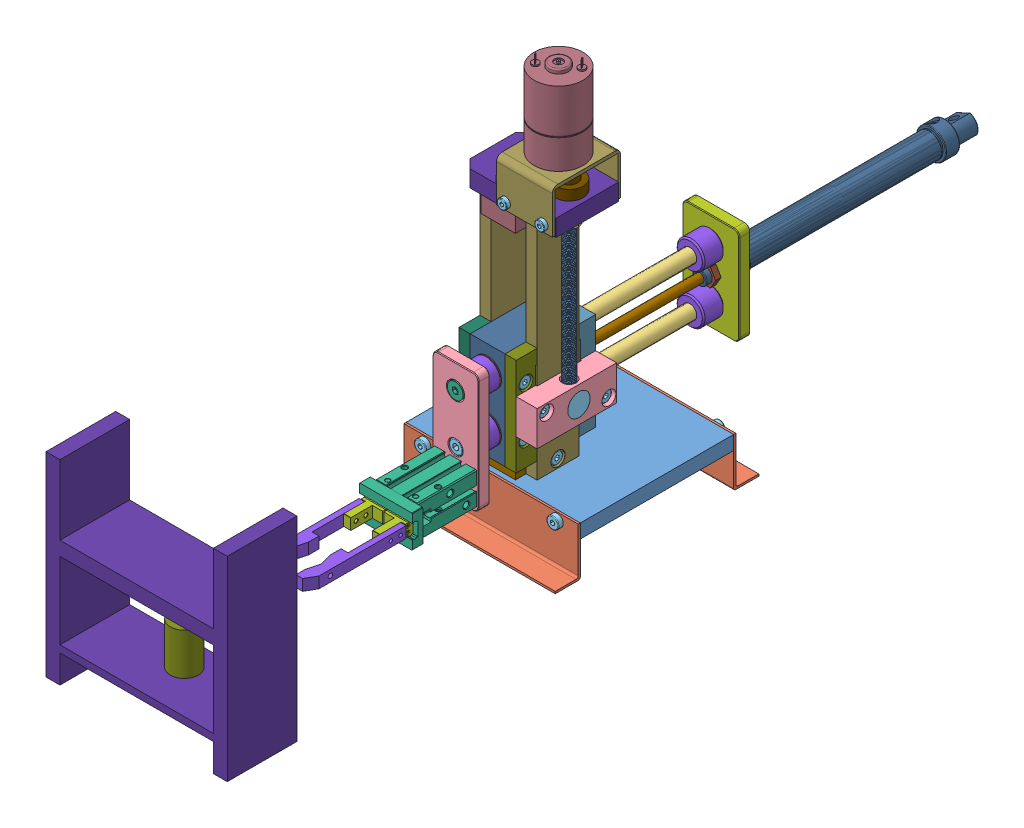
SolidWorks assembly SIm, configuration Default. Lengths in mm.
Overall size (130.9 291 592.3).
74 component instances, 35 part files, 163 mates.
Components (placement in the parent):
- tam_de-1: tam_de [Default] at (55.7373 162.4347 98.3877) size (125 10 110)
- khoi_do-1: khoi_do [Default] at (118.2373 137.4347 153.3877) x (0 0 1) z (0 -1 0) size (18 125 35)
- khoi_do-2: khoi_do [Default] at (-6.7627 137.4347 43.3877) x (0 0 -1) z (0 -1 0) size (18 125 35)
- chot_dan_huong-1: chot_dan_huong [Default] at (55.7373 236.9347 172.3877) x (0.807467 -0.589913 0) z (0.589913 0.807467 0) size (10 175 10)
- chot_dan_huong-2: chot_dan_huong [Default] at (55.7373 201.9347 172.3877) x (0.458763 0.888559 0) z (-0.888559 0.458763 0) size (10 175 10)
- ban_canh_truoc-1: ban_canh_truoc [Default] at (55.7373 211.4347 172.3877) x (1 0 0) z (0 -1 0) size (33 8 86)
- socket head thin cap screw_din-14: socket head thin cap screw_din [DIN 7984 - M5 x 8 --- 5.6N] at (8.2373 167.4347 38.3877) x (0 0 1) z (-1 0 0) size (11.5 8.5 8.5)
- socket head thin cap screw_din-16: socket head thin cap screw_din [DIN 7984 - M5 x 8 --- 5.6N] at (8.2373 167.4347 158.3877) x (0 0 -1) z (1 0 0) size (11.5 8.5 8.5)
- socket head thin cap screw_din-17: socket head thin cap screw_din [DIN 7984 - M5 x 8 --- 5.6N] at (103.2373 167.4347 158.3877) x (0 0 -1) z (1 0 0) size (11.5 8.5 8.5)
- socket head thin cap screw_din-18: socket head thin cap screw_din [DIN 7984 - M5 x 8 --- 5.6N] at (63.2373 164.6347 109.3877) x (0 1 0) z (0 0 1) size (11.5 8.5 8.5)
- socket head thin cap screw_din-19: socket head thin cap screw_din [DIN 7984 - M5 x 8 --- 5.6N] at (48.2373 164.6347 145.3877) x (0 1 0) z (0 0 1) size (11.5 8.5 8.5)
- socket head thin cap screw_din-22: socket head thin cap screw_din [DIN 7984 - M5 x 8 --- 5.6N] at (103.2373 167.4347 38.3877) x (0 0 1) z (-1 0 0) size (11.5 8.5 8.5)
- socket head thin cap screw_din-23: socket head thin cap screw_din [DIN 7984 - M6 x 10 --- 7N] at (55.7373 201.9347 -10.4123) x (0 0 1) z (-1 0 0) size (14 10 10)
- socket head thin cap screw_din-24: socket head thin cap screw_din [DIN 7984 - M6 x 10 --- 7N] at (55.7373 201.6984 180.1877) x (0 0 -1) z (0.997008 0.077294 0) size (14 10 10)
- socket csink head cap screw 10642_din-2: socket csink head cap screw 10642_din [EN ISO 10642 - M6 x 8 - 8N] at (55.7373 236.9347 -10.8323) x (0 0 1) z (-0.997818 -0.066017 0) size (8 11.34 11.34)
- socket csink head cap screw 10642_din-3: socket csink head cap screw 10642_din [EN ISO 10642 - M6 x 8 - 8N] at (55.7373 236.9347 180.6077) x (0 0 -1) z (0.99607 -0.088565 0) size (8 11.34 11.34)
- s3_ban_canh_sau-1: s3_ban_canh_sau [Default] at (55.7373 219.4347 -2.6123) x (-1 0 0) z (0 -1 0) size (41 8 70)
- bac_chan-1: bac_chan [Default] at (55.7373 236.9347 157.3877) x (-0.51421 -0.857665 0) z (-0.857665 0.51421 0) size (20 15 20)
- bac_chan-2: bac_chan [Default] at (55.7373 201.9347 157.3877) x (-0.721448 -0.692468 0) z (-0.692468 0.721448 0) size (20 15 20)
- bac_chan-3: bac_chan [Default] at (55.7373 236.9347 12.3877) x (-0.828899 -0.559398 0) z (0.559398 -0.828899 0) size (20 15 20)
- bac_chan-4: bac_chan [Default] at (55.7373 201.9347 12.3877) x (-0.105421 0.994428 0) z (-0.994428 -0.105421 0) size (20 15 20)
- mieng_dem_duoi-1: mieng_dem_duoi [Default] at (55.7373 172.4347 127.3877) size (25 12 45)
- con_truot_s4_as-1: con_truot_s4_as [Default] at (19.8229 164.1862 110.8419) x (0 0 1) z (0 1 0) size (45 28.02 70)
  - con_truot_s4-1: con_truot_s4 [Default] at (24.0458 23.4144 55.2485) size (45 25 70)
  - bat_lot-1: bat_lot [Default] at (46.5458 35.9144 72.7485) x (0 0.967524 -0.252781) z (0 0.252781 0.967524) size (20 10 20)
  - bat_lot-2: bat_lot [Default] at (46.5458 35.9144 37.7485) x (0 0.967524 -0.252781) z (0 0.252781 0.967524) size (20 10 20)
  - bat_lot-3: bat_lot [Default] at (1.5458 35.9144 72.7485) x (0 0.603074 -0.797685) z (0 -0.797685 -0.603074) size (20 10 20)
  - bat_lot-4: bat_lot [Default] at (1.5458 35.9144 37.7485) x (0 0.603074 -0.797685) z (0 -0.797685 -0.603074) size (20 10 20)
- thanh_dan_huong_lon-1: thanh_dan_huong_lon [Default] at (68.2373 254.9347 127.3877) x (0 0 -1) z (0 -1 0) size (30 8 165)
- thanh_dan_huong_lon-2: thanh_dan_huong_lon [Default] at (43.2373 254.9347 127.3877) x (0 0 -1) z (0 1 0) size (30 8 165)
- mieng_dem_tren-1: mieng_dem_tren [Default] at (55.7373 325.4347 127.3877) size (25 12 45)
- tam_dan_huong-1: tam_dan_huong [Default] at (35.2373 219.4347 106.3877) x (0 0 -1) z (0 -1 0) size (12 41 70)
- thanh_dan_huong_nho_1-1: thanh_dan_huong_nho_1 [Default] at (43.2373 219.4347 149.8877) x (0 0 -1) z (0 1 0) size (15 8 70)
- thanh_dan_huong_nho_2-1: thanh_dan_huong_nho_2 [Default] at (68.2373 219.4347 149.8877) x (0 0 -1) z (0 -1 0) size (15 8 70)
- tam_de_s5-1: tam_de_s5 [Default] at (63.3484 349.4347 127.3877) x (0 0 1) z (1 0 0) size (45 12 67.78)
- dau_kep_truc_vit-1: dau_kep_truc_vit [Default] at (84.2373 339.6347 127.3877) x (0.952744 0 0.303776) z (-0.303776 0 0.952744) size (20 25 20)
- truc_truyen_dong-1: truc_truyen_dong [Default] at (84.2373 208.6347 127.3877) x (0.45612 0 0.889918) z (-0.889918 0 0.45612) size (8.27 150.4 9.24)
- vong_dem-1: vong_dem [Default] at (84.2373 337.4347 127.3877) x (0.916987 0 -0.398918) z (0.398918 0 0.916987) size (19.6 2 19.6)
- hex nut gradec_din-5: hex nut gradec_din [Hexagon Nut ISO 4034 - M8 - N] at (84.2373 329.5347 127.3877) x (-0.92021 0 0.391424) z (0 -1 0) size (13 15.01 7.9)
- thanh_ngang-1: thanh_ngang [Default] at (83.7373 206.9347 128.8877) x (0 0 -1) z (1 0 0) size (57 25 15)
- dai_oc-1: dai_oc [Default] at (77.2373 219.4347 127.3877) x (0 0.924256 0.381773) z (0 0.381773 -0.924256) size (16 14 16)
- socket head thin cap screw_din-25: socket head thin cap screw_din [DIN 7984 - M5 x 8 --- 5.6N] at (89.0373 212.9347 105.8877) x (-1 0 0) z (0 0.924225 0.381849) size (11.5 8.5 8.5)
- socket head thin cap screw_din-26: socket head thin cap screw_din [DIN 7984 - M5 x 8 --- 5.6N] at (89.0373 225.9347 150.3877) x (-1 0 0) z (0 0.924225 0.381849) size (11.5 8.5 8.5)
- socket head thin cap screw_din-27: socket head thin cap screw_din [DIN 7984 - M5 x 8 --- 5.6N] at (75.5373 236.9347 150.3877) x (-1 0 0) z (0 0.924225 0.381849) size (11.5 8.5 8.5)
- socket head thin cap screw_din-28: socket head thin cap screw_din [DIN 7984 - M5 x 8 --- 5.6N] at (75.5373 201.9347 150.3877) x (-1 0 0) z (0 0.924225 0.381849) size (11.5 8.5 8.5)
- socket head thin cap screw_din-29: socket head thin cap screw_din [DIN 7984 - M5 x 8 --- 5.6N] at (75.5373 178.4347 127.3877) x (-1 0 0) z (0 0.924225 0.381849) size (11.5 8.5 8.5)
- socket head thin cap screw_din-30: socket head thin cap screw_din [DIN 7984 - M5 x 8 --- 5.6N] at (35.9373 178.4347 127.3877) size (11.5 8.5 8.5)
- socket head thin cap screw_din-31: socket head thin cap screw_din [DIN 7984 - M5 x 8 --- 5.6N] at (35.9373 201.9347 150.3877) size (11.5 8.5 8.5)
- socket head thin cap screw_din-32: socket head thin cap screw_din [DIN 7984 - M5 x 8 --- 5.6N] at (35.9373 236.9347 150.3877) size (11.5 8.5 8.5)
- socket head thin cap screw_din-33: socket head thin cap screw_din [DIN 7984 - M5 x 8 --- 5.6N] at (35.9373 331.4347 127.3877) size (11.5 8.5 8.5)
- socket head thin cap screw_din-34: socket head thin cap screw_din [DIN 7984 - M5 x 8 --- 5.6N] at (63.2373 248.4347 102.5877) x (0 0 1) z (-1 0 0) size (11.5 8.5 8.5)
- socket head thin cap screw_din-35: socket head thin cap screw_din [DIN 7984 - M5 x 8 --- 5.6N] at (48.2373 190.4347 102.5877) x (0 0 1) z (-1 0 0) size (11.5 8.5 8.5)
- socket head thin cap screw_din-36: socket head thin cap screw_din [DIN 7984 - M5 x 8 --- 5.6N] at (55.7373 352.9347 145.3877) x (0 -1 0) z (0 0 1) size (11.5 8.5 8.5)
- socket head thin cap screw_din-37: socket head thin cap screw_din [DIN 7984 - M5 x 8 --- 5.6N] at (55.7373 352.9347 109.3877) x (0 -1 0) z (0 0 1) size (11.5 8.5 8.5)
- body-2: body [默认] at (55.7373 183.6347 180.3877) x (0 0 -1) z (0 1 0) size (50 38 23.6)
- ljaw-1: ljaw [默认] at (56.1708 183.6347 180.3877) x (0 0 -1) z (0 -1 0) size (21.3 15.4 11.12)
- jaw - ip-2: jaw - ip [Default] at (72.4186 187.6347 268.0848) x (0 0 -1) z (-1 0 0) size (70 8 9.03)
- Part1-1: Part1 [Default] at (55.7373 219.4347 -37.6123) x (0.599964 0.800027 0) z (0.800027 -0.599964 0) size (6.2 165 6.2)
- 16 X 100 Cylinder bore-1: 16 X 100 Cylinder bore [Default] at (55.7373 219.4347 -90.6123) x (-0.421992 0.9066 0) z (0 0 -1) size (21.5 21.5 192)
- hex thin nut gradeb_din-1: hex thin nut gradeb_din [Hexagon Nut ISO 4036 - M8 - N] at (55.7373 219.4347 1.3877) x (0.866025 0.5 0) z (0 0 1) size (13 15.01 4)
- de dong co-1: de dong co [Default] at (96.7373 353.9347 127.4836) x (0 0 1) z (0 -1 0) size (49 40 31)
- moto-1: moto [Default] at (76.7373 371.6519 127.4836) x (0 -1 0) z (-1 0 0) size (63.5 35 35)
- link-1: link [Default] at (91.3829 371.6519 129.7619) x (0 -1 0) z (0.952744 0 0.303776) size (19 10 10)
- socket head thin cap screw_din-39: socket head thin cap screw_din [DIN 7984 - M4 x 6 --- 3.9N] at (63.2373 343.4347 154.7836) x (0 0 -1) z (1 0 0) size (8.8 7 7)
- socket head thin cap screw_din-40: socket head thin cap screw_din [DIN 7984 - M4 x 6 --- 3.9N] at (90.2373 343.4347 100.1836) x (0 0 1) z (-1 0 0) size (8.8 7 7)
- socket head thin cap screw_din-41: socket head thin cap screw_din [DIN 7984 - M4 x 6 --- 3.9N] at (63.2373 343.4347 100.1836) x (0 0 1) z (-1 0 0) size (8.8 7 7)
- socket head thin cap screw_din-44: socket head thin cap screw_din [DIN 7984 - M4 x 6 --- 3.9N] at (90.2373 343.4347 154.7836) x (0 0 -1) z (1 0 0) size (8.8 7 7)
- slotted headless screw_din-5: slotted headless screw_din [DIN 427 M2 x 5 --- 2.4N] at (77.0917 361.1868 125.1094) x (0.952744 0 0.303776) z (-0.303707 -0.021253 0.952528) size (5 2 2)
- socket head thin cap screw_din-45: socket head thin cap screw_din [DIN 7984 - M4 x 10 --- 7.9N] at (66.7373 191.1347 173.9877) x (0 0 1) z (-1 0 0) size (12.8 7 7)
- socket head thin cap screw_din-46: socket head thin cap screw_din [DIN 7984 - M4 x 10 --- 7.9N] at (44.7373 176.1347 173.9877) x (0 0 1) z (-1 0 0) size (12.8 7 7)
- jaw - ip-3: jaw - ip [Default] at (39.056 179.6347 268.0848) x (0 0 -1) z (1 0 0) size (70 8 9.03)
- ljaw-2: ljaw [默认] at (55.3038 183.6347 180.3877) x (0 0 -1) z (0 1 0) size (21.3 15.4 11.12)
- wp-1: wp [Default] at (55.7373 162.4347 374.9086) x (0.821498 0 -0.570212) z (0.570212 0 0.821498) size (20 30 20)
- rack-1: rack [Default] at (52.334 182.4347 355.692) size (130 140 50)
Mates (geometry in assembly coordinates):
- Parallel1: parallel aligned: plane of tam_de-1 through (-6.7627 172.4347 153.3877) normal (0 0 1); plane of khoi_do-1 through (-6.7627 172.4347 154.8877) normal (0 0 1)
- Concentric1: concentric aligned: cylinder of tam_de-1 through (8.2373 167.4347 153.3877) axis (0 0 1) radius 2.1; circle of khoi_do-1
- Concentric2: concentric aligned: circle of tam_de-1; circle of khoi_do-1
- Coincident1: coincident anti-aligned: plane of tam_de-1 through (-6.7627 172.4347 153.3877) normal (0 0 1); plane of khoi_do-1 through (-6.7627 137.4347 153.3877) normal (0 0 -1)
- Parallel2: parallel anti-aligned: plane of tam_de-1 through (-6.7627 172.4347 43.3877) normal (0 0 -1); plane of khoi_do-2 through (118.2373 137.4347 43.3877) normal (0 0 1)
- Concentric3: concentric aligned: circle of tam_de-1; cylinder of khoi_do-2 through (8.2373 167.4347 43.3877) axis (0 0 -1) radius 2.75
- Parallel3: parallel aligned: plane of tam_de-1 through (55.7373 172.4347 98.3877) normal (0 1 0); plane of khoi_do-2 through (118.2373 172.4347 43.3877) normal (0 1 0)
- Coincident2: coincident anti-aligned: plane of tam_de-1 through (-6.7627 172.4347 43.3877) normal (0 0 -1); plane of khoi_do-2 through (118.2373 137.4347 43.3877) normal (0 0 1)
- Concentric18: concentric aligned: cylinder of chot_dan_huong-2 through (55.7373 201.9347 172.3877) axis (0 0 1) radius 2.5; circle of ban_canh_truoc-1
- Concentric19: concentric anti-aligned: circle of chot_dan_huong-1; circle of ban_canh_truoc-1
- Coincident14: coincident aligned: plane of chot_dan_huong-1 through (55.7373 236.9347 172.3877) normal (0 0 1); circle of ban_canh_truoc-1
- Coincident15: coincident aligned: circle of chot_dan_huong-2; plane of ban_canh_truoc-1 through (55.7373 211.4347 172.3877) normal (0 0 -1)
- Concentric37: concentric aligned: cylinder of khoi_do-2 through (8.2373 167.4347 43.3877) axis (0 0 -1) radius 2.75; cylinder of socket head thin cap screw_din-14 through (8.2373 167.4347 6.6377) axis (0 0 -1) radius 4.25
- Coincident28: coincident anti-aligned: plane of khoi_do-2 through (118.2373 172.4347 41.8877) normal (0 0 -1); plane of socket head thin cap screw_din-14 through (8.2373 171.6847 41.8877) normal (0 0 1)
- Concentric39: concentric aligned: cylinder of khoi_do-1 through (8.2373 167.4347 153.3877) axis (0 0 1) radius 2.75; cylinder of socket head thin cap screw_din-16 through (8.2373 167.4347 190.1377) axis (0 0 1) radius 4.25
- Coincident30: coincident anti-aligned: plane of khoi_do-1 through (-6.7627 172.4347 154.8877) normal (0 0 1); plane of socket head thin cap screw_din-16 through (8.2373 171.6847 154.8877) normal (0 0 -1)
- Concentric40: concentric aligned: cylinder of khoi_do-1 through (103.2373 167.4347 153.3877) axis (0 0 1) radius 2.75; cylinder of socket head thin cap screw_din-17 through (103.2373 167.4347 190.1377) axis (0 0 1) radius 4.25
- Coincident31: coincident anti-aligned: plane of khoi_do-1 through (-6.7627 172.4347 154.8877) normal (0 0 1); plane of socket head thin cap screw_din-17 through (103.2373 171.6847 154.8877) normal (0 0 -1)
- Concentric41: concentric aligned: cylinder of tam_de-1 through (63.2373 172.4347 109.3877) axis (0 -1 0) radius 2.75; cylinder of socket head thin cap screw_din-18 through (63.2373 132.8847 109.3877) axis (0 -1 0) radius 4.25
- Coincident32: coincident anti-aligned: plane of tam_de-1 through (63.2373 168.1347 109.3877) normal (0 -1 0); plane of socket head thin cap screw_din-18 through (58.9873 168.1347 109.3877) normal (0 1 0)
- Concentric42: concentric aligned: cylinder of tam_de-1 through (48.2373 172.4347 145.3877) axis (0 -1 0) radius 2.75; cylinder of socket head thin cap screw_din-19 through (48.2373 132.8847 145.3877) axis (0 -1 0) radius 4.25
- Coincident33: coincident anti-aligned: plane of tam_de-1 through (48.2373 168.1347 145.3877) normal (0 -1 0); plane of socket head thin cap screw_din-19 through (43.9873 168.1347 145.3877) normal (0 1 0)
- Concentric451: concentric aligned: cylinder of khoi_do-2 through (103.2373 167.4347 43.3877) axis (0 0 -1) radius 2.75; cylinder of socket head thin cap screw_din-22 through (103.2373 167.4347 6.6377) axis (0 0 -1) radius 4.25
- Coincident361: coincident anti-aligned: plane of khoi_do-2 through (118.2373 172.4347 41.8877) normal (0 0 -1); plane of socket head thin cap screw_din-22 through (103.2373 171.6847 41.8877) normal (0 0 1)
- Concentric47: concentric aligned: cylinder of ban_canh_truoc-1 through (55.7373 201.6984 176.1877) axis (0 0 1) radius 5.5; cylinder of socket head thin cap screw_din-24 through (55.7373 201.6984 211.9377) axis (0 0 1) radius 5
- Coincident38: coincident anti-aligned: plane of ban_canh_truoc-1 through (55.7373 201.6984 176.1877) normal (0 0 1); plane of socket head thin cap screw_din-24 through (55.3508 206.6834 176.1877) normal (0 0 -1)
- Coincident40: coincident aligned: cone of ban_canh_truoc-1 through (55.7373 236.9347 177.1877) axis (0 0 -1); cylinder of socket csink head cap screw 10642_din-3 through (55.7373 236.9347 179.5577) axis (0 0 -1) radius 785.3982
- Concentric452: concentric aligned: circle of chot_dan_huong-2; circle of s3_ban_canh_sau-1
- Coincident362: coincident anti-aligned: plane of chot_dan_huong-1 through (55.7373 236.9347 -2.6123) normal (0 0 -1); plane of s3_ban_canh_sau-1 through (55.7373 219.4347 -2.6123) normal (0 0 1)
- Concentric453: concentric anti-aligned: cylinder of socket csink head cap screw 10642_din-2 through (55.7373 236.9347 -10.8323) axis (0 0 -1) radius 3; cylinder of s3_ban_canh_sau-1 through (55.7373 236.9347 -10.6123) axis (0 0 1) radius 3.3
- Coincident363: coincident aligned: cylinder of socket csink head cap screw 10642_din-2 through (55.7373 236.9347 -9.7823) axis (0 0 1) radius 785.3982; cylinder of s3_ban_canh_sau-1 through (55.7373 236.9347 -7.4123) axis (0 0 1) radius 785.3982
- Concentric454: concentric aligned: cylinder of chot_dan_huong-2 through (55.7373 201.9347 -2.6123) axis (0 0 -1) radius 2.5; cylinder of socket head thin cap screw_din-23 through (55.7373 201.9347 -42.1623) axis (0 0 -1) radius 3
- Coincident364: coincident anti-aligned: plane of socket head thin cap screw_din-23 through (55.7373 206.9347 -6.4123) normal (0 0 1); plane of s3_ban_canh_sau-1 through (55.7373 201.9347 -6.4123) normal (0 0 -1)
- Concentric456: concentric anti-aligned: cylinder of chot_dan_huong-1 through (55.7373 236.9347 -2.6123) axis (0 0 1) radius 5; cylinder of bac_chan-1 through (55.7373 236.9347 172.3877) axis (0 0 -1) radius 5
- Coincident366: coincident anti-aligned: plane of ban_canh_truoc-1 through (55.7373 211.4347 172.3877) normal (0 0 -1); plane of bac_chan-1 through (55.7373 236.9347 172.3877) normal (0 0 1)
- Concentric457: concentric anti-aligned: cylinder of chot_dan_huong-2 through (55.7373 201.9347 -2.6123) axis (0 0 1) radius 5; circle of bac_chan-2
- Coincident367: coincident anti-aligned: plane of ban_canh_truoc-1 through (55.7373 211.4347 172.3877) normal (0 0 -1); plane of bac_chan-2 through (55.7373 201.9347 172.3877) normal (0 0 1)
- Concentric458: concentric anti-aligned: cylinder of chot_dan_huong-1 through (55.7373 236.9347 -2.6123) axis (0 0 1) radius 5; circle of bac_chan-3
- Coincident368: coincident anti-aligned: plane of s3_ban_canh_sau-1 through (55.7373 219.4347 -2.6123) normal (0 0 1); plane of bac_chan-3 through (55.7373 236.9347 -2.6123) normal (0 0 -1)
- Concentric459: concentric anti-aligned: cylinder of chot_dan_huong-2 through (55.7373 201.9347 -2.6123) axis (0 0 1) radius 5; circle of bac_chan-4
- Coincident369: coincident anti-aligned: plane of s3_ban_canh_sau-1 through (55.7373 219.4347 -2.6123) normal (0 0 1); plane of bac_chan-4 through (55.7373 201.9347 -2.6123) normal (0 0 -1)
- Concentric460: concentric anti-aligned: cylinder of socket head thin cap screw_din-19 through (48.2373 132.8847 145.3877) axis (0 -1 0) radius 2.5; cylinder of mieng_dem_duoi-1 through (48.2373 184.4347 145.3877) axis (0 1 0) radius 2.1
- Concentric461: concentric anti-aligned: cylinder of socket head thin cap screw_din-18 through (63.2373 132.8847 109.3877) axis (0 -1 0) radius 2.5; cylinder of mieng_dem_duoi-1 through (63.2373 184.4347 109.3877) axis (0 1 0) radius 2.1
- Coincident371: coincident anti-aligned: plane of tam_de-1 through (55.7373 172.4347 98.3877) normal (0 1 0); plane of mieng_dem_duoi-1 through (55.7373 172.4347 127.3877) normal (0 -1 0)
- Parallel6: parallel anti-aligned: plane of mieng_dem_duoi-1 through (55.7373 184.4347 127.3877) normal (0 1 0); plane of con_truot_s4_as-1/con_truot_s4-1 through (226.6799 184.4347 112.3877) normal (0 -1 0)
- Parallel7: parallel aligned: plane of mieng_dem_duoi-1 through (68.2373 184.4347 149.8877) normal (1 0 0); plane of con_truot_s4_as-1/con_truot_s4-1 through (68.2373 219.4347 134.8877) normal (1 0 0)
- Coincident372: coincident aligned: plane of mieng_dem_duoi-1 through (68.2373 184.4347 149.8877) normal (1 0 0); plane of con_truot_s4_as-1/con_truot_s4-1 through (68.2373 219.4347 134.8877) normal (1 0 0)
- Concentric464: concentric aligned: cylinder of chot_dan_huong-2 through (55.7373 201.9347 -2.6123) axis (0 0 1) radius 5; cylinder of con_truot_s4_as-1/bat_lot-2 through (55.7373 201.9347 147.3877) axis (0 0 1) radius 5
- Concentric465: concentric aligned: cylinder of chot_dan_huong-1 through (55.7373 236.9347 -2.6123) axis (0 0 1) radius 5; circle of con_truot_s4_as-1/con_truot_s4-1
- Parallel9: parallel aligned: plane of con_truot_s4_as-1/con_truot_s4-1 through (68.2373 219.4347 134.8877) normal (1 0 0); plane of thanh_dan_huong_lon-1 through (76.2373 254.9347 127.3877) normal (1 0 0)
- Concentric466: concentric anti-aligned: circle of mieng_dem_duoi-1; circle of thanh_dan_huong_lon-1
- Parallel10: parallel aligned: plane of con_truot_s4_as-1/con_truot_s4-1 through (68.2373 270.4347 112.3877) normal (0 0 -1); plane of thanh_dan_huong_lon-1 through (76.2373 172.4347 112.3877) normal (0 0 -1)
- Coincident374: coincident anti-aligned: plane of mieng_dem_duoi-1 through (68.2373 184.4347 149.8877) normal (1 0 0); plane of thanh_dan_huong_lon-1 through (68.2373 254.9347 127.3877) normal (-1 0 0)
- Parallel11: parallel: line of thanh_dan_huong_lon-1 through (68.2373 337.3347 112.4877) axis (0 -1 0); plane of thanh_dan_huong_lon-2 through (35.2373 337.4347 142.3877) normal (0 0 1)
- Parallel12: parallel aligned: plane of thanh_dan_huong_lon-1 through (68.2373 254.9347 127.3877) normal (-1 0 0); plane of thanh_dan_huong_lon-2 through (35.2373 254.9347 127.3877) normal (-1 0 0)
- Concentric467: concentric anti-aligned: cylinder of mieng_dem_duoi-1 through (68.2373 178.4347 127.3877) axis (1 0 0) radius 2.1; circle of thanh_dan_huong_lon-2
- Coincident375: coincident anti-aligned: plane of mieng_dem_duoi-1 through (43.2373 184.4347 149.8877) normal (-1 0 0); plane of thanh_dan_huong_lon-2 through (43.2373 254.9347 127.3877) normal (1 0 0)
- Concentric468: concentric aligned: cylinder of thanh_dan_huong_lon-2 through (39.4373 331.4347 127.3877) axis (-1 0 0) radius 5; cylinder of mieng_dem_tren-1 through (43.2373 331.4347 127.3877) axis (-1 0 0) radius 2.1
- Parallel13: parallel aligned: plane of mieng_dem_duoi-1 through (55.7373 184.4347 127.3877) normal (0 1 0); plane of mieng_dem_tren-1 through (55.7373 337.4347 127.3877) normal (0 1 0)
- Coincident376: coincident anti-aligned: plane of thanh_dan_huong_lon-2 through (43.2373 254.9347 127.3877) normal (1 0 0); plane of mieng_dem_tren-1 through (43.2373 337.4347 149.8877) normal (-1 0 0)
- Parallel14: parallel anti-aligned: plane of con_truot_s4_as-1/con_truot_s4-1 through (68.2373 270.4347 112.3877) normal (0 0 -1); plane of tam_dan_huong-1 through (76.2373 244.4347 111.3877) normal (0 0 1)
- Parallel15: parallel anti-aligned: plane of con_truot_s4_as-1/con_truot_s4-1 through (193.5245 254.4347 112.3877) normal (0 1 0); plane of tam_dan_huong-1 through (76.2373 184.4347 112.3877) normal (0 -1 0)
- Concentric469: concentric aligned: circle of con_truot_s4_as-1/con_truot_s4-1; circle of tam_dan_huong-1
- Coincident377: coincident anti-aligned: plane of con_truot_s4_as-1/con_truot_s4-1 through (68.2373 270.4347 112.3877) normal (0 0 -1); plane of tam_dan_huong-1 through (76.2373 244.4347 112.3877) normal (0 0 1)
- Concentric470: concentric anti-aligned: circle of con_truot_s4_as-1/con_truot_s4-1; circle of thanh_dan_huong_nho_1-1
- Concentric474: concentric anti-aligned: cylinder of con_truot_s4_as-1/con_truot_s4-1 through (68.2373 201.9347 150.3877) axis (1 0 0) radius 2.1; cylinder of thanh_dan_huong_nho_1-1 through (39.4373 201.9347 150.3877) axis (-1 0 0) radius 5
- Coincident378: coincident anti-aligned: plane of con_truot_s4_as-1/con_truot_s4-1 through (43.2373 219.4347 134.8877) normal (-1 0 0); plane of thanh_dan_huong_nho_1-1 through (43.2373 219.4347 149.8877) normal (1 0 0)
- Coincident379: coincident anti-aligned: plane of thanh_dan_huong_lon-2 through (35.2373 337.4347 112.3877) normal (0 0 -1); plane of tam_dan_huong-1 through (76.2373 244.4347 112.3877) normal (0 0 1)
- Concentric475: concentric anti-aligned: circle of con_truot_s4_as-1/con_truot_s4-1; circle of thanh_dan_huong_nho_2-1
- Concentric476: concentric anti-aligned: circle of con_truot_s4_as-1/con_truot_s4-1; circle of thanh_dan_huong_nho_2-1
- Coincident380: coincident anti-aligned: plane of con_truot_s4_as-1/con_truot_s4-1 through (68.2373 219.4347 134.8877) normal (1 0 0); plane of thanh_dan_huong_nho_2-1 through (68.2373 219.4347 149.8877) normal (-1 0 0)
- Coincident381: coincident anti-aligned: plane of s3_ban_canh_sau-1 through (55.7373 219.4347 -2.6123) normal (0 0 1); plane of bac_chan-3 through (55.7373 236.9347 -2.6123) normal (0 0 -1)
- Concentric477: concentric aligned: circle of s3_ban_canh_sau-1; circle of bac_chan-3
- Axis Y: limit distance = 0 mm anti-aligned: plane of con_truot_s4_as-1/con_truot_s4-1 through (226.6799 184.4347 112.3877) normal (0 -1 0); plane of mieng_dem_duoi-1 through (55.7373 184.4347 127.3877) normal (0 1 0)
- Parallel16: parallel anti-aligned: plane of mieng_dem_tren-1 through (55.7373 337.4347 127.3877) normal (0 1 0); plane of tam_de_s5-1 through (63.3484 337.4347 127.3877) normal (0 -1 0)
- Parallel17: parallel anti-aligned: plane of thanh_dan_huong_lon-1 through (76.2373 254.9347 127.3877) normal (1 0 0); plane of tam_de_s5-1 through (29.4595 337.4347 110.8877) normal (-1 0 0)
- Concentric478: concentric anti-aligned: cylinder of tam_de_s5-1 through (84.2373 337.4347 127.3877) axis (0 1 0) radius 7; cylinder of dau_kep_truc_vit-1 through (84.2373 349.4347 127.3877) axis (0 -1 0) radius 7
- Coincident382: coincident anti-aligned: plane of tam_de_s5-1 through (63.3484 349.4347 127.3877) normal (0 1 0); plane of dau_kep_truc_vit-1 through (84.2373 349.4347 127.3877) normal (0 -1 0)
- Concentric479: concentric aligned: cylinder of mieng_dem_tren-1 through (55.7373 337.4347 145.3877) axis (0 1 0) radius 2.1; cylinder of tam_de_s5-1 through (55.7373 337.4347 145.3877) axis (0 1 0) radius 2.75
- Coincident383: coincident anti-aligned: plane of mieng_dem_tren-1 through (55.7373 337.4347 127.3877) normal (0 1 0); plane of tam_de_s5-1 through (63.3484 337.4347 127.3877) normal (0 -1 0)
- Concentric480: concentric anti-aligned: cylinder of dau_kep_truc_vit-1 through (84.2373 339.6347 127.3877) axis (0 -1 0) radius 3.4; circle of truc_truyen_dong-1
- Coincident384: coincident anti-aligned: plane of dau_kep_truc_vit-1 through (84.2373 356.6347 127.3877) normal (0 -1 0); plane of truc_truyen_dong-1 through (84.2373 356.6347 127.3877) normal (0 1 0)
- Concentric481: concentric aligned: cylinder of tam_de_s5-1 through (84.2373 339.9347 127.3877) axis (0 -1 0) radius 10; cylinder of vong_dem-1 through (84.2373 339.4347 127.3877) axis (0 -1 0) radius 9.8
- Coincident385: coincident aligned: plane of tam_de_s5-1 through (63.3484 337.4347 127.3877) normal (0 -1 0); plane of vong_dem-1 through (84.2373 337.4347 127.3877) normal (0 -1 0)
- Concentric484: concentric aligned: cylinder of vong_dem-1 through (84.2373 339.4347 127.3877) axis (0 -1 0) radius 4.25; cylinder of hex nut gradec_din-5 through (84.2373 354.5722 127.3877) axis (0 -1 0) radius 4
- Coincident387: coincident anti-aligned: plane of vong_dem-1 through (84.2373 337.4347 127.3877) normal (0 -1 0); plane of hex nut gradec_din-5 through (81.2995 337.4347 120.481) normal (0 1 0)
- Lock1: lock: unknown of dau_kep_truc_vit-1; unknown of vong_dem-1
- Lock2: lock: unknown of vong_dem-1; unknown of hex nut gradec_din-5
- Lock3: lock: unknown of truc_truyen_dong-1; unknown of hex nut gradec_din-5
- Parallel18: parallel aligned: plane of thanh_dan_huong_lon-1 through (76.2373 254.9347 127.3877) normal (1 0 0); plane of thanh_ngang-1 through (91.2373 231.9347 157.3877) normal (1 0 0)
- Parallel19: parallel aligned: plane of thanh_dan_huong_nho_2-1 through (76.2373 184.4347 157.3877) normal (0 0 1); plane of thanh_ngang-1 through (91.2373 231.9347 157.3877) normal (0 0 1)
- Concentric485: concentric aligned: cylinder of thanh_dan_huong_nho_2-1 through (76.2373 225.9347 150.3877) axis (1 0 0) radius 2.1; cylinder of thanh_ngang-1 through (76.2373 225.9347 150.3877) axis (1 0 0) radius 2.75
- Coincident388: coincident anti-aligned: plane of thanh_dan_huong_nho_2-1 through (76.2373 219.4347 149.8877) normal (1 0 0); plane of thanh_ngang-1 through (76.2373 231.9347 157.3877) normal (-1 0 0)
- Concentric486: concentric anti-aligned: circle of truc_truyen_dong-1; cylinder of dai_oc-1 through (84.2373 227.4347 127.3877) axis (0 1 0) radius 3.4
- Concentric487: concentric aligned: circle of thanh_ngang-1; circle of dai_oc-1
- Concentric488: concentric aligned: cylinder of thanh_ngang-1 through (76.2373 212.9347 105.8877) axis (1 0 0) radius 2.75; cylinder of socket head thin cap screw_din-25 through (120.7873 212.9347 105.8877) axis (1 0 0) radius 4.25
- Coincident389: coincident anti-aligned: plane of thanh_ngang-1 through (85.5373 212.9347 105.8877) normal (1 0 0); plane of socket head thin cap screw_din-25 through (85.5373 211.3118 109.8157) normal (-1 0 0)
- Concentric489: concentric aligned: cylinder of thanh_ngang-1 through (76.2373 225.9347 150.3877) axis (1 0 0) radius 2.75; cylinder of socket head thin cap screw_din-26 through (120.7873 225.9347 150.3877) axis (1 0 0) radius 4.25
- Coincident390: coincident anti-aligned: plane of thanh_ngang-1 through (85.5373 225.9347 150.3877) normal (1 0 0); plane of socket head thin cap screw_din-26 through (85.5373 224.3118 154.3157) normal (-1 0 0)
- Concentric490: concentric aligned: cylinder of thanh_dan_huong_nho_2-1 through (72.0373 236.9347 150.3877) axis (1 0 0) radius 5; cylinder of socket head thin cap screw_din-27 through (107.2873 236.9347 150.3877) axis (1 0 0) radius 4.25
- Coincident391: coincident anti-aligned: plane of thanh_dan_huong_nho_2-1 through (72.0373 236.9347 150.3877) normal (1 0 0); plane of socket head thin cap screw_din-27 through (72.0373 235.3118 154.3157) normal (-1 0 0)
- Concentric491: concentric aligned: cylinder of thanh_dan_huong_nho_2-1 through (72.0373 201.9347 150.3877) axis (1 0 0) radius 5; cylinder of socket head thin cap screw_din-28 through (107.2873 201.9347 150.3877) axis (1 0 0) radius 4.25
- Coincident392: coincident anti-aligned: plane of thanh_dan_huong_nho_2-1 through (72.0373 201.9347 150.3877) normal (1 0 0); plane of socket head thin cap screw_din-28 through (72.0373 200.3118 154.3157) normal (-1 0 0)
- Concentric492: concentric aligned: cylinder of thanh_dan_huong_lon-1 through (72.0373 178.4347 127.3877) axis (1 0 0) radius 5; cylinder of socket head thin cap screw_din-29 through (107.2873 178.4347 127.3877) axis (1 0 0) radius 4.25
- Coincident393: coincident anti-aligned: plane of thanh_dan_huong_lon-1 through (72.0373 178.4347 127.3877) normal (1 0 0); plane of socket head thin cap screw_din-29 through (72.0373 176.8118 131.3157) normal (-1 0 0)
- Concentric493: concentric anti-aligned: cylinder of thanh_dan_huong_lon-2 through (35.2373 178.4347 127.3877) axis (1 0 0) radius 2.75; cylinder of socket head thin cap screw_din-30 through (4.1873 178.4347 127.3877) axis (-1 0 0) radius 4.25
- Coincident394: coincident anti-aligned: plane of thanh_dan_huong_lon-2 through (39.4373 178.4347 127.3877) normal (-1 0 0); plane of socket head thin cap screw_din-30 through (39.4373 182.6847 127.3877) normal (1 0 0)
- Concentric494: concentric aligned: cylinder of thanh_dan_huong_nho_1-1 through (39.4373 201.9347 150.3877) axis (-1 0 0) radius 5; cylinder of socket head thin cap screw_din-31 through (4.1873 201.9347 150.3877) axis (-1 0 0) radius 4.25
- Coincident395: coincident anti-aligned: plane of thanh_dan_huong_nho_1-1 through (39.4373 201.9347 150.3877) normal (-1 0 0); plane of socket head thin cap screw_din-31 through (39.4373 206.1847 150.3877) normal (1 0 0)
- Concentric495: concentric aligned: cylinder of thanh_dan_huong_nho_1-1 through (39.4373 236.9347 150.3877) axis (-1 0 0) radius 5; cylinder of socket head thin cap screw_din-32 through (4.1873 236.9347 150.3877) axis (-1 0 0) radius 4.25
- Coincident396: coincident anti-aligned: plane of thanh_dan_huong_nho_1-1 through (39.4373 236.9347 150.3877) normal (-1 0 0); plane of socket head thin cap screw_din-32 through (39.4373 241.1847 150.3877) normal (1 0 0)
- Concentric496: concentric aligned: cylinder of thanh_dan_huong_lon-2 through (39.4373 331.4347 127.3877) axis (-1 0 0) radius 5; cylinder of socket head thin cap screw_din-33 through (4.1873 331.4347 127.3877) axis (-1 0 0) radius 4.25
- Coincident397: coincident anti-aligned: plane of thanh_dan_huong_lon-2 through (39.4373 331.4347 127.3877) normal (-1 0 0); plane of socket head thin cap screw_din-33 through (39.4373 335.6847 127.3877) normal (1 0 0)
- Concentric497: concentric aligned: cylinder of tam_dan_huong-1 through (63.2373 248.4347 112.3877) axis (0 0 -1) radius 2.75; cylinder of socket head thin cap screw_din-34 through (63.2373 248.4347 70.8377) axis (0 0 -1) radius 4.25
- Coincident398: coincident anti-aligned: plane of tam_dan_huong-1 through (63.2373 248.4347 106.0877) normal (0 0 -1); plane of socket head thin cap screw_din-34 through (63.2373 252.6847 106.0877) normal (0 0 1)
- Concentric498: concentric aligned: cylinder of tam_dan_huong-1 through (48.2373 190.4347 112.3877) axis (0 0 -1) radius 2.75; cylinder of socket head thin cap screw_din-35 through (48.2373 190.4347 70.8377) axis (0 0 -1) radius 4.25
- Coincident399: coincident anti-aligned: plane of tam_dan_huong-1 through (48.2373 190.4347 106.0877) normal (0 0 -1); plane of socket head thin cap screw_din-35 through (48.2373 194.6847 106.0877) normal (0 0 1)
- Concentric499: concentric aligned: cylinder of tam_de_s5-1 through (55.7373 337.4347 145.3877) axis (0 1 0) radius 2.75; cylinder of socket head thin cap screw_din-36 through (55.7373 384.6847 145.3877) axis (0 1 0) radius 4.25
- Coincident401: coincident anti-aligned: plane of tam_de_s5-1 through (63.3484 349.4347 127.3877) normal (0 1 0); plane of socket head thin cap screw_din-36 through (59.9873 349.4347 145.3877) normal (0 -1 0)
- Concentric500: concentric aligned: cylinder of tam_de_s5-1 through (55.7373 337.4347 109.3877) axis (0 1 0) radius 2.75; cylinder of socket head thin cap screw_din-37 through (55.7373 384.6847 109.3877) axis (0 1 0) radius 4.25
- Coincident402: coincident anti-aligned: plane of tam_de_s5-1 through (63.3484 349.4347 127.3877) normal (0 1 0); plane of socket head thin cap screw_din-37 through (59.9873 349.4347 109.3877) normal (0 -1 0)
- Concentric507: concentric aligned: cylinder of ban_canh_truoc-1 through (44.7373 176.1347 180.3877) axis (0 0 -1) radius 2.25; cylinder of body-2 through (44.7373 176.1347 184.8272) axis (0 0 -1) radius 1.621
- Coincident405: coincident anti-aligned: plane of ban_canh_truoc-1 through (55.7373 211.4347 180.3877) normal (0 0 1); plane of body-2 through (55.7373 183.6347 180.3877) normal (0 0 -1)
- Concentric509: concentric aligned: cylinder of ban_canh_truoc-1 through (66.7373 191.1347 180.3877) axis (0 0 -1) radius 2.25; cylinder of body-2 through (66.7373 191.1347 184.8272) axis (0 0 -1) radius 1.621
- Concentric510: concentric anti-aligned: cylinder of body-2 through (36.7373 188.7947 228.6877) axis (-1 0 0) radius 0.4; cylinder of ljaw-1 through (11.1708 188.7947 228.6877) axis (1 0 0) radius 0.4
- Parallel20: parallel aligned: plane of body-2 through (55.7373 183.6347 230.3877) normal (0 0 1); plane of ljaw-1 through (56.1808 179.6347 232.1877) normal (0 0 1)
- Gripper: limit distance = 0.4435 mm: point of ljaw-1; moEndPointRef_w of body-2
- Concentric514: concentric aligned: cylinder of ljaw-1 through (66.1258 183.6347 236.6877) axis (1 0 0) radius 1.2295; cylinder of jaw - ip-2 through (72.6308 183.6347 236.6877) axis (1 0 0) radius 1.25
- Concentric515: concentric aligned: cylinder of ljaw-1 through (66.1258 183.6347 243.6877) axis (1 0 0) radius 1.2295; cylinder of jaw - ip-2 through (72.6308 183.6347 243.6877) axis (1 0 0) radius 1.25
- Coincident407: coincident anti-aligned: plane of ljaw-1 through (68.6308 183.6347 180.3877) normal (1 0 0); plane of jaw - ip-2 through (68.6308 179.6347 270.368) normal (-1 0 0)
- Axis Z: limit distance = 0 mm anti-aligned: plane of bac_chan-1 through (55.7373 236.9347 157.3877) normal (0 0 -1); plane of con_truot_s4_as-1/con_truot_s4-1 through (68.2373 270.4347 157.3877) normal (0 0 1)
- Concentric518: concentric aligned: cylinder of con_truot_s4_as-1/con_truot_s4-1 through (55.7373 219.4347 112.3877) axis (0 0 -1) radius 2.1; cylinder of Part1-1 through (55.7373 219.4347 108.3877) axis (0 0 -1) radius 2.6
- Coincident408: coincident anti-aligned: circle of con_truot_s4_as-1/con_truot_s4-1; plane of Part1-1 through (55.7373 219.4347 127.3877) normal (0 0 1)
- Concentric519: concentric anti-aligned: cylinder of Part1-1 through (55.7373 219.4347 127.3877) axis (0 0 -1) radius 3.1; cylinder of 16 X 100 Cylinder bore-1 through (55.7373 219.4347 -169.6123) axis (0 0 1) radius 3.25
- Coincident409: coincident anti-aligned: plane of s3_ban_canh_sau-1 through (55.7373 219.4347 -6.4123) normal (0 0 -1); plane of 16 X 100 Cylinder bore-1 through (55.7373 219.4347 -6.4123) normal (0 0 1)
- Concentric521: concentric aligned: cylinder of 16 X 100 Cylinder bore-1 through (55.7373 219.4347 -37.0085) axis (0 0 1) radius 5.1; cylinder of hex thin nut gradeb_din-1 through (55.7373 219.4347 -23.6498) axis (0 0 1) radius 4
- Coincident410: coincident anti-aligned: plane of s3_ban_canh_sau-1 through (55.7373 219.4347 -2.6123) normal (0 0 1); plane of hex thin nut gradeb_din-1 through (51.9845 225.9347 -2.6123) normal (0 0 -1)
- Parallel24: parallel aligned: plane of s3_ban_canh_sau-1 through (76.2373 254.4347 -10.6123) normal (0 1 0); plane of hex thin nut gradeb_din-1 through (59.4901 225.9347 -2.6123) normal (0 1 0)
- Concentric522: concentric anti-aligned: cylinder of tam_de_s5-1 through (90.2373 343.4347 149.8877) axis (0 0 1) radius 1.65; cylinder of de dong co-1 through (90.2373 343.4347 178.9836) axis (0 0 -1) radius 2.25
- Concentric523: concentric anti-aligned: cylinder of tam_de_s5-1 through (63.2373 343.4347 149.8877) axis (0 0 1) radius 1.65; cylinder of de dong co-1 through (63.2373 343.4347 178.9836) axis (0 0 -1) radius 2.25
- Coincident411: coincident anti-aligned: plane of tam_de_s5-1 through (97.2373 337.4347 149.8877) normal (0 0 1); plane of de dong co-1 through (-366.2627 367.0879 149.8877) normal (0 0 -1)
- Concentric525: concentric aligned: cylinder of moto-1 through (84.2373 383.5768 127.4836) axis (0 -1 0) radius 5; cylinder of link-1 through (84.2373 364.9347 127.4836) axis (0 -1 0) radius 5
- Coincident413: coincident anti-aligned: plane of moto-1 through (76.7373 369.4347 127.4836) normal (0 -1 0); plane of link-1 through (91.3829 369.4347 129.7619) normal (0 1 0)
- Concentric527: concentric aligned: cylinder of de dong co-1 through (84.2373 359.4347 127.4836) axis (0 1 0) radius 6; cylinder of moto-1 through (84.2373 364.4347 127.4836) axis (0 1 0) radius 6
- Parallel26: parallel aligned: plane of de dong co-1 through (56.7373 353.9347 127.4836) normal (-1 0 0); plane of moto-1 through (78.5373 376.3203 130.2456) normal (-1 0 0)
- Parallel27: parallel aligned: plane of dau_kep_truc_vit-1 through (79.7256 364.6347 123.4324) normal (-0.952744 0 -0.303776); plane of link-1 through (82.3318 363.4347 126.876) normal (-0.952744 0 -0.303776)
- Coincident414: coincident anti-aligned: plane of de dong co-1 through (56.7373 369.4347 102.9836) normal (0 1 0); plane of moto-1 through (76.7373 369.4347 127.4836) normal (0 -1 0)
- Concentric529: concentric anti-aligned: cylinder of de dong co-1 through (63.2373 343.4347 178.9836) axis (0 0 -1) radius 2.25; cylinder of socket head thin cap screw_din-39 through (63.2373 343.4347 186.5336) axis (0 0 1) radius 3.5
- Coincident416: coincident anti-aligned: plane of de dong co-1 through (56.7373 369.4347 151.9836) normal (0 0 1); plane of socket head thin cap screw_din-39 through (63.2373 346.9347 151.9836) normal (0 0 -1)
- Concentric530: concentric aligned: cylinder of de dong co-1 through (90.2373 343.4347 178.9836) axis (0 0 -1) radius 2.25; cylinder of socket head thin cap screw_din-40 through (90.2373 343.4347 68.4336) axis (0 0 -1) radius 3.5
- Coincident417: coincident anti-aligned: plane of de dong co-1 through (56.7373 369.4347 102.9836) normal (0 0 -1); plane of socket head thin cap screw_din-40 through (90.2373 346.9347 102.9836) normal (0 0 1)
- Concentric531: concentric aligned: cylinder of de dong co-1 through (63.2373 343.4347 178.9836) axis (0 0 -1) radius 2.25; cylinder of socket head thin cap screw_din-41 through (63.2373 343.4347 68.4336) axis (0 0 -1) radius 3.5
- Coincident418: coincident anti-aligned: plane of de dong co-1 through (56.7373 369.4347 102.9836) normal (0 0 -1); plane of socket head thin cap screw_din-41 through (63.2373 346.9347 102.9836) normal (0 0 1)
- Concentric533: concentric anti-aligned: cylinder of de dong co-1 through (90.2373 343.4347 178.9836) axis (0 0 -1) radius 2.25; cylinder of socket head thin cap screw_din-44 through (90.2373 343.4347 186.5336) axis (0 0 1) radius 3.5
- Coincident419: coincident anti-aligned: plane of de dong co-1 through (56.7373 369.4347 151.9836) normal (0 0 1); plane of socket head thin cap screw_din-44 through (90.2373 346.9347 151.9836) normal (0 0 -1)
- Concentric537: concentric aligned: cylinder of dau_kep_truc_vit-1 through (78.9972 361.1868 125.717) axis (-0.952744 0 -0.303776) radius 0.8; cylinder of slotted headless screw_din-5 through (73.5893 361.1868 123.9927) axis (-0.952744 0 -0.303776) radius 1
- Distance3: distance = 2 mm aligned: plane of slotted headless screw_din-5 through (77.0917 361.1868 125.1094) normal (-0.952744 0 -0.303776); plane of dau_kep_truc_vit-1 through (79.7256 364.6347 123.4324) normal (-0.952744 0 -0.303776)
- Concentric538: concentric aligned: cylinder of ban_canh_truoc-1 through (66.7373 191.1347 176.7877) axis (0 0 -1) radius 4; cylinder of socket head thin cap screw_din-45 through (66.7373 191.1347 142.2377) axis (0 0 -1) radius 3.5
- Coincident420: coincident anti-aligned: plane of ban_canh_truoc-1 through (66.7373 191.1347 176.7877) normal (0 0 -1); plane of socket head thin cap screw_din-45 through (66.7373 194.6347 176.7877) normal (0 0 1)
- Concentric539: concentric aligned: cylinder of ban_canh_truoc-1 through (44.7373 176.1347 176.7877) axis (0 0 -1) radius 4; cylinder of socket head thin cap screw_din-46 through (44.7373 176.1347 142.2377) axis (0 0 -1) radius 3.5
- Coincident421: coincident anti-aligned: plane of ban_canh_truoc-1 through (44.7373 176.1347 176.7877) normal (0 0 -1); plane of socket head thin cap screw_din-46 through (44.7373 179.6347 176.7877) normal (0 0 1)
- Parallel28: parallel: line of tam_de-1 through (-6.7627 162.4347 153.3877) axis (1 0 0); plane of rack-1 through (52.334 182.4347 355.692) normal (0 0 -1)
- Coincident422: coincident aligned: plane of khoi_do-1 through (-6.7627 137.4347 153.3877) normal (0 -1 0); plane of rack-1 through (52.334 137.4347 405.692) normal (0 -1 0)
